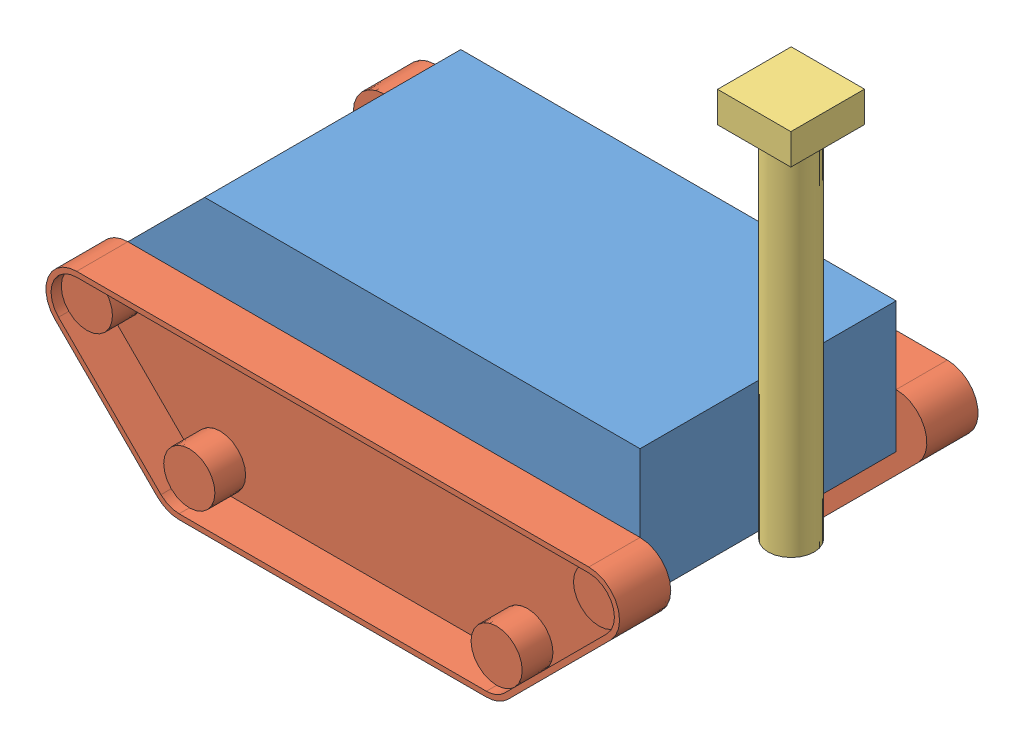
SolidWorks assembly Assemblage1, configuration Défaut. Lengths in mm.
Overall size (1248.23 975.26 700).
4 component instances, 3 part files, 7 mates.
Components (placement in the parent):
- pièce caisse simple-1: pièce caisse simple [Défaut] at (-802.8452 44.1484 -250) size (1000 360 500)
- pièce chenille simple-1: pièce chenille simple [Défaut] at (-490.5606 2.1947 250) size (1120 320 100)
- pièce chenille simple-2: pièce chenille simple [Défaut] at (394.636 2.1947 -250) x (-1 0 0) z (0 0 -1) size (1120 320 100)
- Poteau replié simple-2: Poteau replié simple [Défaut] at (493.6013 670.7216 3.7145) x (-0.708742 0 0.705468) z (0 -1 0) size (202.85 202.85 760)
Mates (geometry in assembly coordinates):
- Coïncidente1: coincident anti-aligned: plane of pièce caisse simple-1 through (-47.9623 -781.3621 250) normal (0 0 1); plane of pièce chenille simple-1 through (-47.9623 -990.6926 250) normal (0 0 -1)
- Coïncidente2: coincident: point of pièce caisse simple-1; point of pièce chenille simple-1
- Coïncidente7: coincident anti-aligned: plane of pièce caisse simple-1 through (-47.9623 -781.3621 -250) normal (0 0 -1); plane of pièce chenille simple-2 through (-47.9623 -990.6926 -250) normal (0 0 1)
- Parallèle1: parallel aligned: line of pièce caisse simple-1 through (452.0377 225.4643 -250) axis (-1 0 0); line of pièce chenille simple-2 through (452.0377 75.4643 -250) axis (-1 0 0)
- Coïncidente9: coincident: point of pièce caisse simple-1; point of pièce chenille simple-2
- Coaxiale1: concentric anti-aligned: circle of Poteau replié simple-2; circle of assembly
- Parallèle3: parallel anti-aligned: line of pièce caisse simple-1 through (452.0377 225.4643 250) axis (0 0 -1); line of Poteau replié simple-2 through (425.2916 670.7216 -71.8934) axis (0 0 1)
